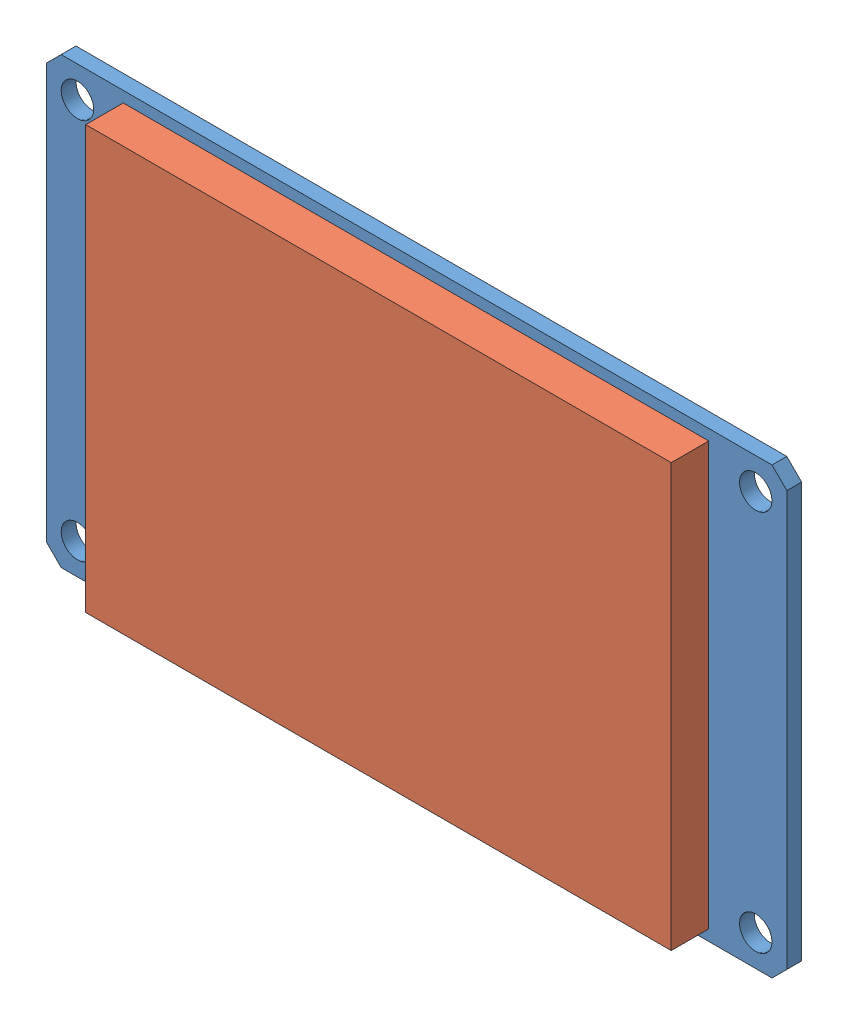
SolidWorks assembly AssemOvenPCB, configuration Default. Lengths in mm.
Overall size (75 45 5.3).
2 component instances, 2 part files, 6 mates.
Components (placement in the parent):
- OvenPCB-1: OvenPCB [Default] at origin size (75 45 1.5)
- LCD ER-TFT-1: LCD ER-TFT [Default] at (-0.0606 0 1.5) size (59.3 42.8 3.8)
Mates (geometry in assembly coordinates):
- Coincident1: coincident aligned: plane of OvenPCB-1 through (0 0 0) normal (0 0 1); plane of assembly through (0 0 0) normal (0 0 1)
- Coincident2: coincident aligned: plane of OvenPCB-1 through (0 0 0) normal (0 1 0); plane of assembly through (0 0 0) normal (0 1 0)
- Coincident3: coincident aligned: plane of OvenPCB-1 through (0 0 0) normal (1 0 0); plane of assembly through (0 0 0) normal (1 0 0)
- Coincident4: coincident anti-aligned: plane of OvenPCB-1 through (0 0 1.5) normal (0 0 1); plane of LCD ER-TFT-1 through (-0.0606 0 1.5) normal (0 0 -1)
- Coincident5: coincident aligned: plane of LCD ER-TFT-1 through (-0.0606 0 1.5) normal (0 1 0); plane of assembly through (0 0 0) normal (0 1 0)
- Distance1: distance = 9 mm aligned: plane of LCD ER-TFT-1 through (-31 21.4 5.3) normal (-1 0 0); plane of OvenPCB-1 through (-40 25 1.5) normal (-1 0 0)
